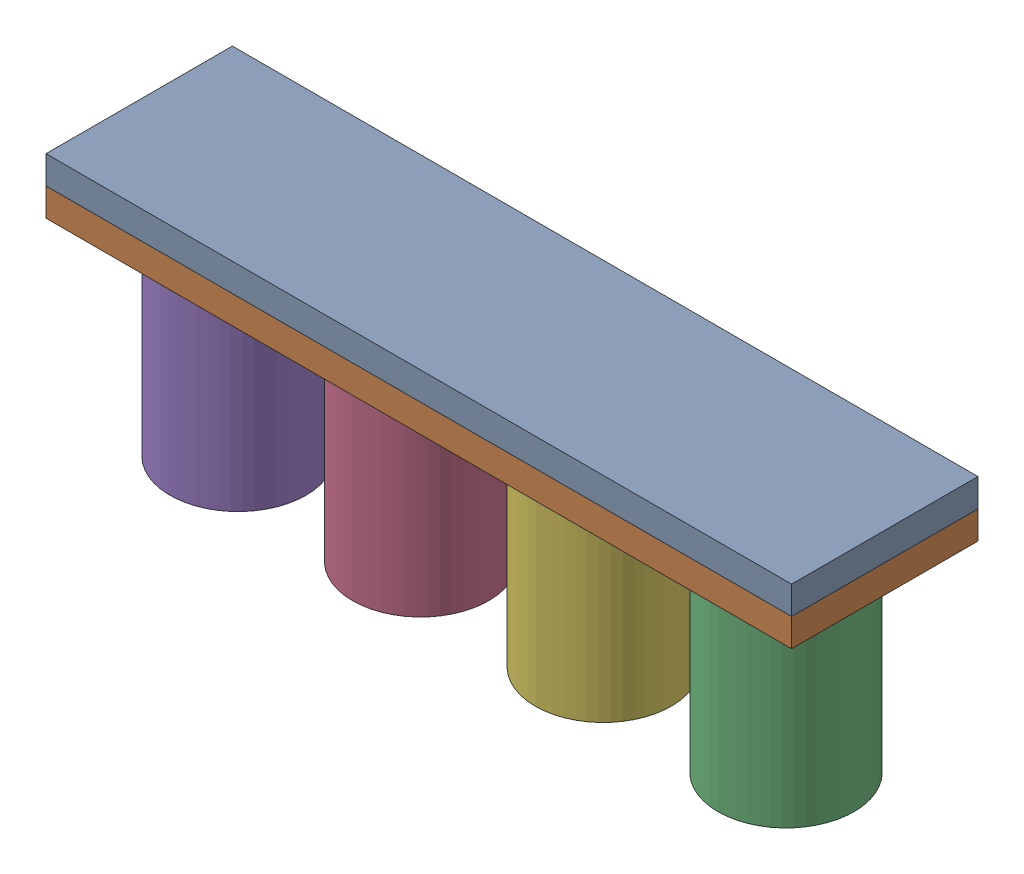
SolidWorks assembly Assemblage_Elements_De_Jeu, configuration Défaut. Lengths in mm.
Overall size (400 139 100).
6 component instances, 2 part files, 11 mates.
Components (placement in the parent):
- Element_De_Jeu_Plate-Forme-1: Element_De_Jeu_Plate-Forme [Défaut] at (-244.2956 45.5711 50) size (400 15 100)
- Element_De_Jeu_Plate-Forme-2: Element_De_Jeu_Plate-Forme [Défaut] at (-244.2956 30.5711 50) size (400 15 100)
- Element_De_Jeu_Colonne-1: Element_De_Jeu_Colonne [Défaut] at (102.7044 -78.4289 0) size (73 109 73)
- Element_De_Jeu_Colonne-2: Element_De_Jeu_Colonne [Défaut] at (-93.2956 -78.4289 0) size (73 109 73)
- Element_De_Jeu_Colonne-3: Element_De_Jeu_Colonne [Défaut] at (-191.2956 -78.4289 0) x (-0.305592 0 0.952163) z (-0.952163 0 -0.305592) size (73 109 73)
- Element_De_Jeu_Colonne-4: Element_De_Jeu_Colonne [Défaut] at (4.7044 -78.4289 0) size (73 109 73)
Mates (geometry in assembly coordinates):
- Coïncidente1: coincident aligned: plane of Element_De_Jeu_Plate-Forme-1 through (-244.2956 60.5711 50) normal (-1 0 0); plane of Element_De_Jeu_Plate-Forme-2 through (-244.2956 45.5711 50) normal (-1 0 0)
- Coïncidente2: coincident aligned: plane of Element_De_Jeu_Plate-Forme-1 through (-244.2956 60.5711 50) normal (0 0 1); plane of Element_De_Jeu_Plate-Forme-2 through (-244.2956 45.5711 50) normal (0 0 1)
- Coïncidente3: coincident anti-aligned: plane of Element_De_Jeu_Plate-Forme-1 through (-244.2956 45.5711 50) normal (0 -1 0); plane of Element_De_Jeu_Plate-Forme-2 through (-244.2956 45.5711 50) normal (0 1 0)
- Coïncidente4: coincident aligned: plane of Element_De_Jeu_Colonne-2 through (-93.2956 30.5711 0) normal (0 1 0); plane of Element_De_Jeu_Colonne-3 through (-191.2956 30.5711 0) normal (0 1 0)
- Coïncidente5: coincident aligned: plane of Element_De_Jeu_Colonne-1 through (102.7044 30.5711 0) normal (0 1 0); plane of Element_De_Jeu_Colonne-2 through (-93.2956 30.5711 0) normal (0 1 0)
- Coïncidente6: coincident aligned: plane of Element_De_Jeu_Colonne-1 through (102.7044 30.5711 0) normal (0 1 0); plane of Element_De_Jeu_Colonne-4 through (4.7044 30.5711 0) normal (0 1 0)
- Coïncidente7: coincident anti-aligned: plane of Element_De_Jeu_Plate-Forme-2 through (-244.2956 30.5711 50) normal (0 -1 0); plane of Element_De_Jeu_Colonne-3 through (-191.2956 30.5711 0) normal (0 1 0)
- Coïncidente8: coincident aligned: cylinder of Element_De_Jeu_Colonne-3 through (-191.2956 30.5711 0) axis (0 -1 0) radius 36.5
- Coïncidente9: coincident aligned: cylinder of Element_De_Jeu_Colonne-2 through (-93.2956 30.5711 0) axis (0 -1 0) radius 36.5
- Coïncidente10: coincident aligned: cylinder of Element_De_Jeu_Colonne-4 through (4.7044 30.5711 0) axis (0 -1 0) radius 36.5
- Coïncidente11: coincident aligned: cylinder of Element_De_Jeu_Colonne-1 through (102.7044 30.5711 0) axis (0 -1 0) radius 36.5
